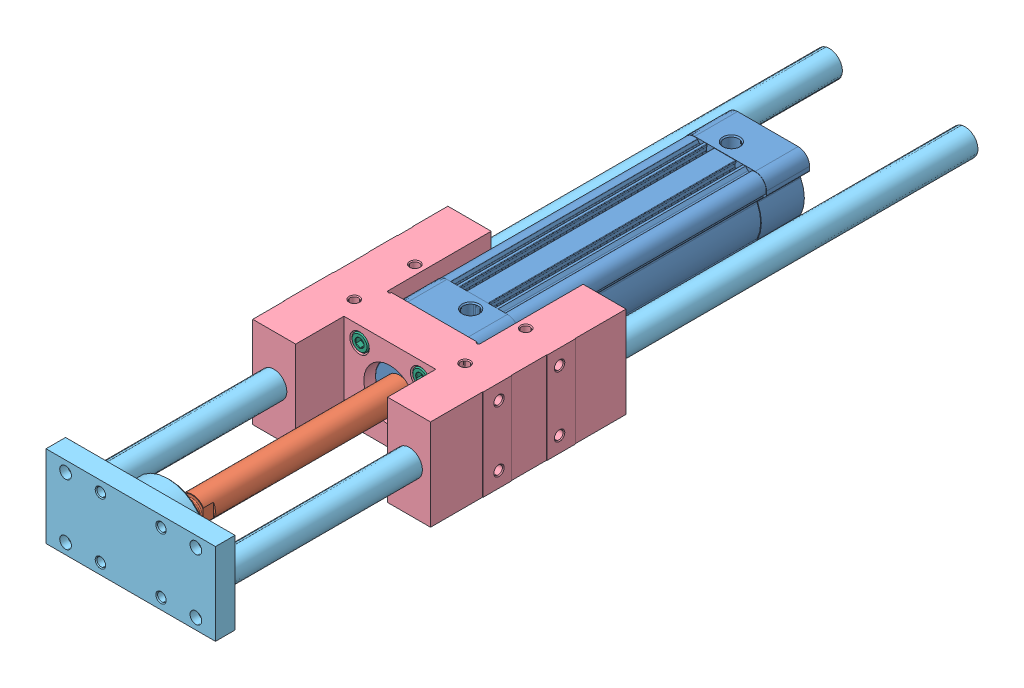
SolidWorks assembly Prensa com suporte especial, configuration Default. Lengths in mm.
Overall size (137 70 588).
10 component instances, 6 part files, 10 mates.
Components (placement in the parent):
- 1463770_DSBC_50_150_PPSA__Z_0_-1: 1463770_DSBC_50_150_PPSA__Z_0_ [Default] at origin size (64 64 286.8)
- 1463770_DSBC_50_150__K_-1: 1463770_DSBC_50_150__K_ [Default] at (0 0 150) size (50 50 290.8)
- DIN_439_B___M16x1_5_F_-1: DIN_439_B___M16x1_5_F_ [Default] at (0 0 199.8) x (1 0 0) z (0 -1 0) size (24 8 27.71)
- 150292 FENG-50-400-KF---(asm_0)-1: 150292 FENG-50-400-KF---(asm_0) [Default] at origin size (137 70 588) (flexible)
  - 150292 FENG-50-KF---(GK)-1: 150292 FENG-50-KF---(GK) [Default] at origin size (137 70 150)
  - 150292 FENG-50-400-KF---(JS)-1: 150292 FENG-50-400-KF---(JS) [Default] at (0 0 143.8) size (130 63 588)
  - DIN-912 - M8x40(F)-1: DIN-912 - M8x40(F) [Default] at (23.25 23.25 26) x (1 0 0) z (0 -1 0) size (13 48.35 13)
  - DIN-912 - M8x40(F)-2: DIN-912 - M8x40(F) [Default] at (-23.25 23.25 26) x (1 0 0) z (0 -1 0) size (13 48.35 13)
  - DIN-912 - M8x40(F)-3: DIN-912 - M8x40(F) [Default] at (23.25 -23.25 26) x (1 0 0) z (0 -1 0) size (13 48.35 13)
  - DIN-912 - M8x40(F)-4: DIN-912 - M8x40(F) [Default] at (-23.25 -23.25 26) x (1 0 0) z (0 -1 0) size (13 48.35 13)
Mates (geometry in assembly coordinates):
- LimitDistance1: limit distance = 150 mm anti-aligned: plane of 1463770_DSBC_50_150_PPSA__Z_0_-1 through (0 0 -223) normal (0 0 1); plane of 1463770_DSBC_50_150__K_-1 through (0 0 -73) normal (0 0 -1)
- Coincident1: coincident anti-aligned: line of 1463770_DSBC_50_150_PPSA__Z_0_-1 through (0 0 80.9) axis (0 0 -1); line of 1463770_DSBC_50_150__K_-1 through (0 0 100) axis (0 0 1)
- Angle2: planar angle = 1.570796 rad anti-aligned: plane of 1463770_DSBC_50_150__K_-1 through (0 0 150) normal (0 1 0); plane of 1463770_DSBC_50_150_PPSA__Z_0_-1 through (0 0 0) normal (1 0 0)
- Distance1: distance = 0 mm anti-aligned: plane of 1463770_DSBC_50_150__K_-1 through (0 0 199.8) normal (0 0 -1); plane of DIN_439_B___M16x1_5_F_-1 through (0 0 199.8) normal (0 0 1)
- Coincident2: coincident anti-aligned: line of 1463770_DSBC_50_150__K_-1 through (0 0 69.1) axis (0 0 1); line of DIN_439_B___M16x1_5_F_-1 through (0 0 249.8) axis (0 0 -1)
- Angle5: planar angle = 0 rad aligned: plane of DIN_439_B___M16x1_5_F_-1 through (0 0 199.8) normal (1 0 0); plane of 1463770_DSBC_50_150__K_-1 through (0 0 150) normal (1 0 0)
- Concentric5: concentric aligned: cylinder of 1463770_DSBC_50_150_PPSA__Z_0_-1 through (23.25 -23.25 -22.1188) axis (0 0 1) radius 3.3235; cylinder of 150292 FENG-50-400-KF---(asm_0)-1/DIN-912 - M8x40(F)-3 through (23.25 -23.25 -14) axis (0 0 1) radius 4
- Concentric6: concentric aligned: cylinder of 1463770_DSBC_50_150_PPSA__Z_0_-1 through (23.25 23.25 -22.1188) axis (0 0 1) radius 3.3235; cylinder of 150292 FENG-50-400-KF---(asm_0)-1/DIN-912 - M8x40(F)-1 through (23.25 23.25 -14) axis (0 0 1) radius 4
- Coincident3: coincident anti-aligned: plane of 1463770_DSBC_50_150_PPSA__Z_0_-1 through (-31 20.3934 0) normal (0 0 1); plane of 150292 FENG-50-400-KF---(asm_0)-1/150292 FENG-50-KF---(GK)-1 through (32.75 35 0) normal (0 0 -1)
- Coincident4: coincident anti-aligned: plane of 1463770_DSBC_50_150__K_-1 through (0 0 217.8) normal (0 0 1); plane of 150292 FENG-50-400-KF---(asm_0)-1/150292 FENG-50-400-KF---(JS)-1 through (0 0 217.8) normal (0 0 -1)
